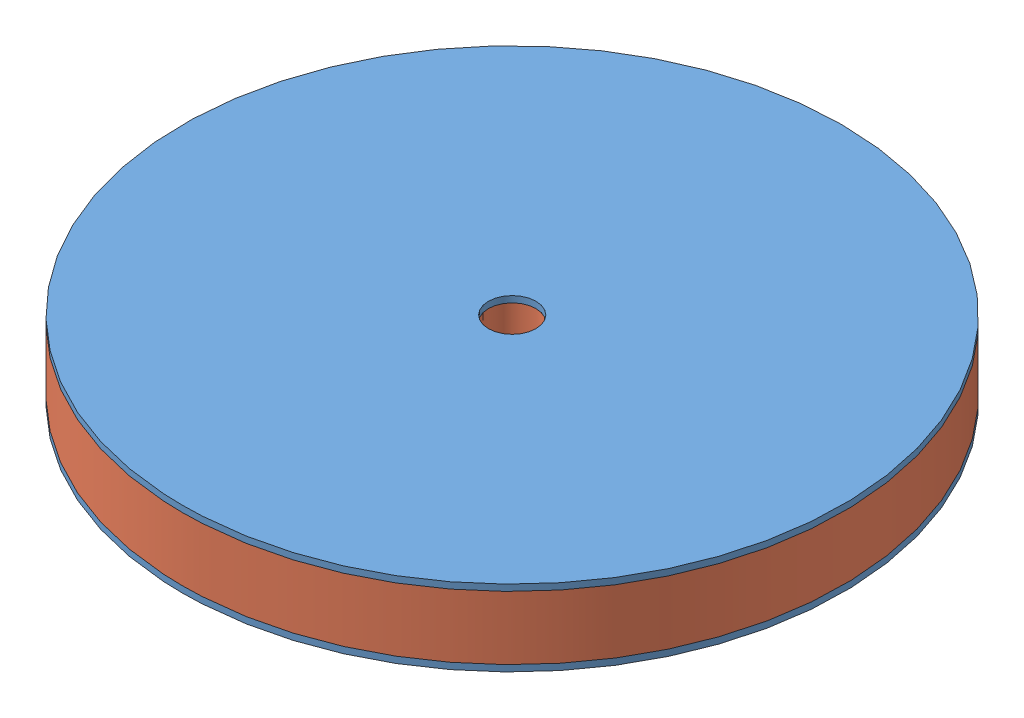
SolidWorks assembly Assem1, configuration Default. Lengths in mm.
Overall size (132.08 15.24 132.08).
3 component instances, 2 part files, 4 mates.
Components (placement in the parent):
- CarbonBulkhead-1: CarbonBulkhead [Default] at (46.664 70.3016 101.4091) size (132.08 1.27 132.08)
- CarbonBulkhead-2: CarbonBulkhead [Default] at (46.664 84.2716 101.4091) size (132.08 1.27 132.08)
- BulkheadBasic-1: BulkheadBasic [Default] at (46.664 71.5716 101.4091) size (132.08 12.7 132.08)
Mates (geometry in assembly coordinates):
- Coincident1: coincident anti-aligned: plane of CarbonBulkhead-1 through (46.664 71.5716 101.4091) normal (0 1 0); plane of BulkheadBasic-1 through (46.664 71.5716 101.4091) normal (0 -1 0)
- Coincident2: coincident anti-aligned: plane of CarbonBulkhead-2 through (46.664 84.2716 101.4091) normal (0 -1 0); plane of BulkheadBasic-1 through (46.664 84.2716 101.4091) normal (0 1 0)
- Concentric1: concentric aligned: circle of CarbonBulkhead-1; circle of CarbonBulkhead-2
- Concentric2: concentric aligned: circle of CarbonBulkhead-2; circle of BulkheadBasic-1
